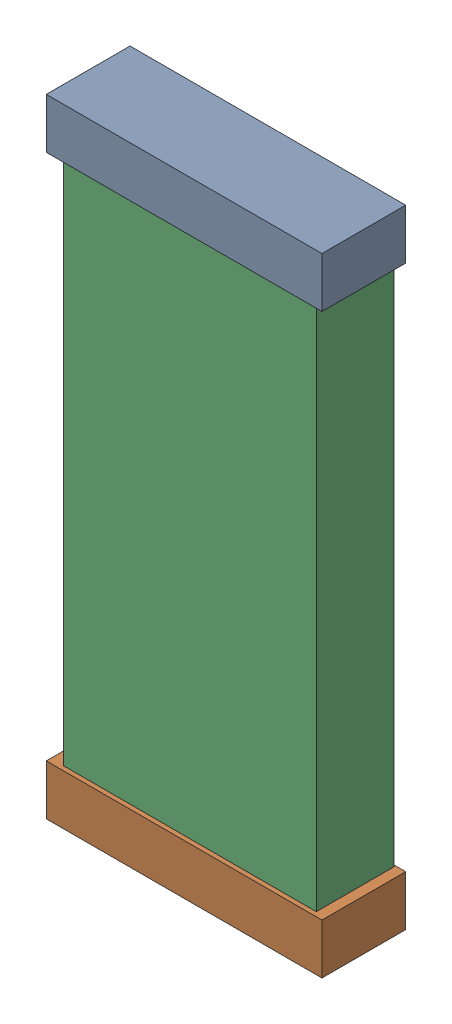
SolidWorks assembly C23, configuration Default. Lengths in mm.
Overall size (1.51 3.44 0.46).
6 component instances, 2 part files, 0 mates.
Components (placement in the parent):
- 744575856-1: 744575856 [Default] at (21.3499 47.7499 -0.8715) size (1.51 0.28 0.46)
  - Extruded (27)-1: Extruded (27) [Default] at origin size (1.51 0.28 0.46)
- 744575856_1-1: 744575856_1 [Default] at (21.35 44.5875 -0.8715) size (1.51 0.28 0.46)
  - Extruded (27)-1: Extruded (27) [Default] at origin size (1.51 0.28 0.46)
- 710423568-1: 710423568 [Default] at (21.3579 46.175 -0.8615) size (1.38 3.05 0.42)
  - Extruded (28)-1: Extruded (28) [Default] at origin size (1.38 3.05 0.42)
